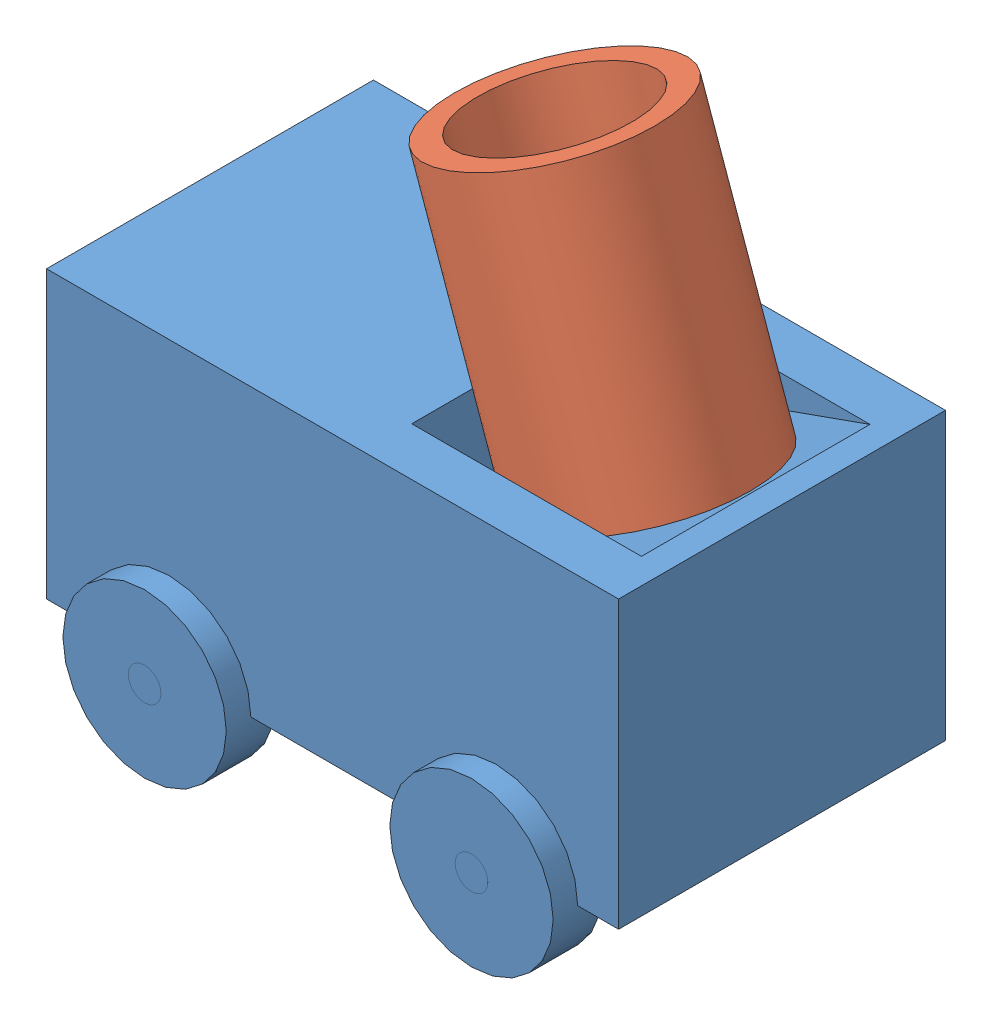
SolidWorks assembly Assem7, configuration Default. Lengths in mm.
Overall size (73.22 78.91 46).
5 component instances, 4 part files, 1 mates.
Components (placement in the parent):
- Part7-1: Part7 [Default] at origin size (70 45 46)
- assem3-1: assem3 [Default] at (-23.7595 -21.4701 41.9088) x (0.887633 0.315817 0.335212) z (-0.335212 0.942143 0) size (26 26 44.86)
  - cannon2-1: cannon2 [Default] at (5.2175 24.7365 13.1686) size (26 26 35)
  - cannon3-1: cannon3 [Default] at (5.2175 24.7365 13.3102) size (19.9 19.9 15)
- grip6-1: grip6 [Default] at (-70 -5.6702 20.7479) size (0 8 8)
Mates (geometry in assembly coordinates):
- Coincident2: coincident anti-aligned: circle of Part7-1; circle of assem3-1/cannon3-1
